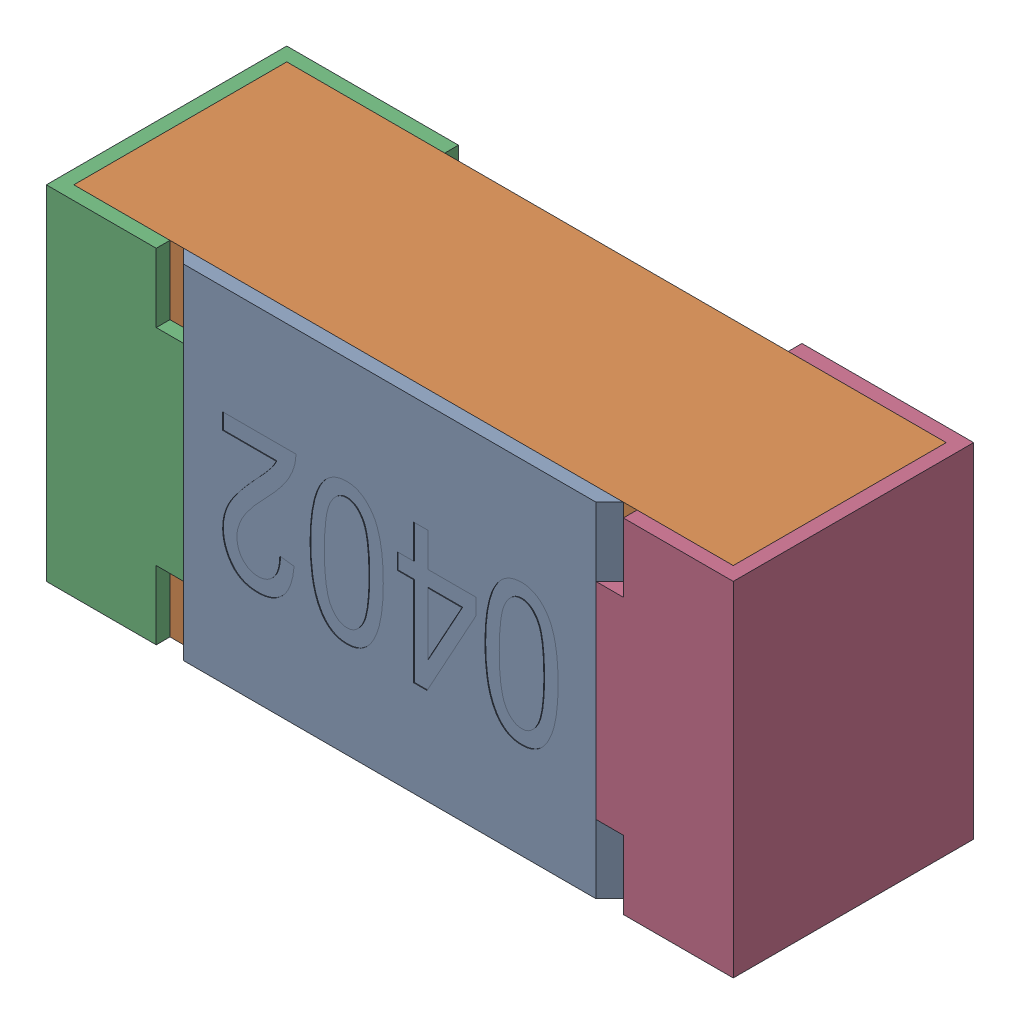
SolidWorks assembly R34, configuration Standard. Lengths in mm.
Overall size (1 0.5 0.35).
5 component instances, 4 part files, 0 mates.
Components (placement in the parent):
- R34-subassembly-1-1: R34-subassembly-1 [Standard] at (1.0999 -5.5 0) x (-1 0 0) z (0 0 1) size (1 0.5 0.35)
  - User Library-R_0402-1: User Library-R_0402 [Standard] at origin size (0.64 0.5 0.02)
  - User Library-R_0402-1-1: User Library-R_0402-1 [Standard] at origin size (0.96 0.5 0.31)
  - User Library-R_0402-2-1: User Library-R_0402-2 [Standard] at origin size (0.25 0.5 0.35)
  - User Library-R_0402-3-1: User Library-R_0402-3 [Standard] at origin size (0.25 0.5 0.35)
